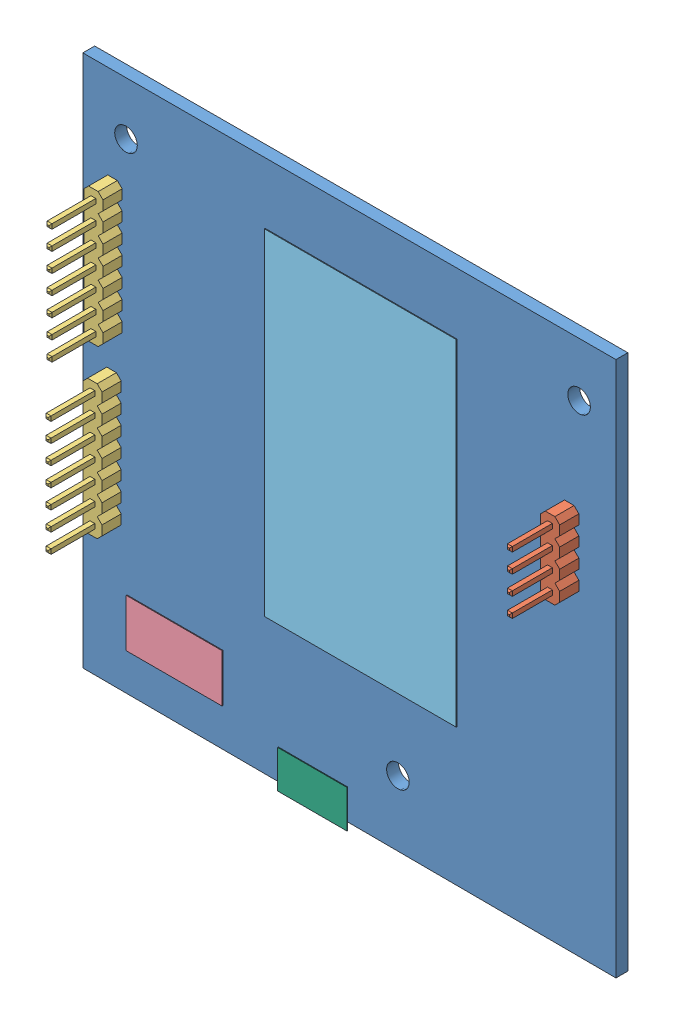
SolidWorks assembly ConnectorBoard v1, configuration Standard. Lengths in mm.
Overall size (70.59 71.77 11.84).
8 component instances, 6 part files, 3 mates.
Components (placement in the parent):
- PCB Component-1: PCB Component [Standard] at origin size (70.59 71.77 11.84)
  - Board-1: Board [Standard] at origin size (70.59 70.92 1.57)
  - 1X04-1: 1X04 [Standard] at (64.389 46.101 1.57) x (0 -1 0) z (0 0 1) size (10.16 2.54 11.34)
  - 1X07-1: 1X07 [Standard] at (3.81 27.178 1.57) x (0 -1 0) z (0 0 1) size (17.78 2.54 11.54)
  - 1X07-2: 1X07 [Standard] at (3.937 49.276 1.57) x (0 -1 0) z (0 0 1) size (17.78 2.54 11.54)
  - 22-23-2051-1: 22-23-2051 [Standard] at (12.192 8.128 1.57) x (-1 0 0) z (0 0 1) size (12.7 6.35 0.1)
  - ESP32-DEVKITV1-1: ESP32-DEVKITV1 [Standard] at (36.83 40.894 1.57) size (25.4 44.45 0.1)
  - USB-MICRO-SMD-1: USB-MICRO-SMD [Standard] at (30.48 0.889 1.57) x (0 1 0) z (0 0 1) size (5 9.17 0.1)
Mates (geometry in assembly coordinates):
- Deckungsgleich1: coincident: plane of PCB Component-1/Board-1 through (0 0 0) normal (0 1 0)
- Deckungsgleich2: coincident: plane of PCB Component-1/Board-1 through (0 0 0) normal (1 0 0)
- Deckungsgleich3: coincident aligned: plane of PCB Component-1/Board-1 through (0 0 0) normal (0 0 1)
